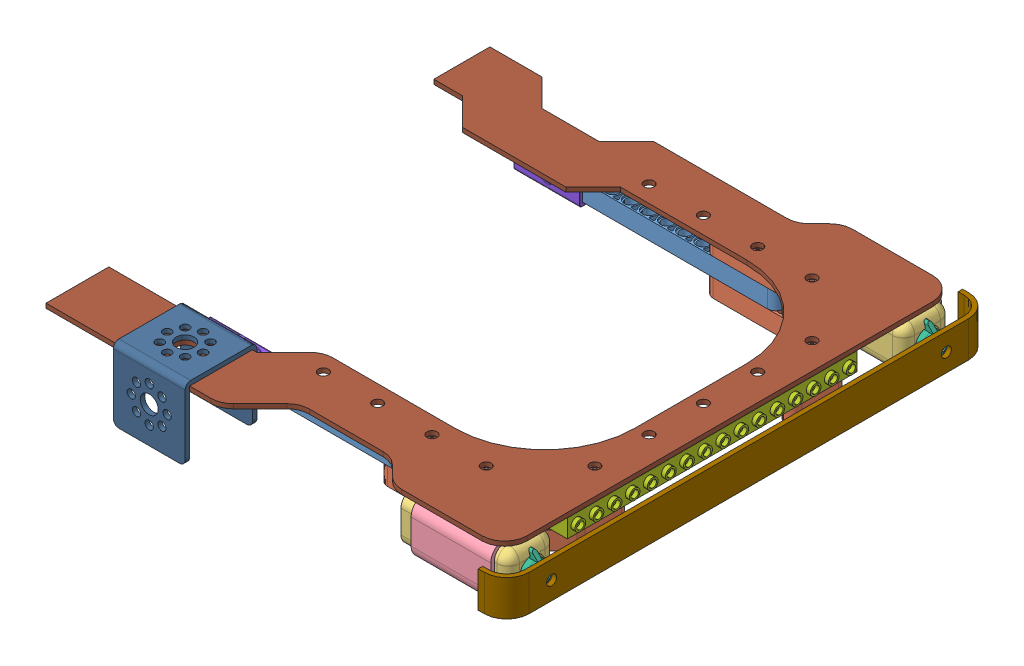
SolidWorks assembly Bump Sensor Assembly, configuration Default. Lengths in mm.
Overall size (205.36 32 217.88).
22 component instances, 11 part files, 41 mates.
Components (placement in the parent):
- Beam 15-1: Beam 15 [Default] at (-13.6618 55.1538 95.9616) size (120.35 8.06 7.44)
- Beam 15-2: Beam 15 [Default] at (-13.6618 55.1538 -49.2084) size (120.35 8.06 7.44)
- Beam Angle 9x5-1: Beam Angle 9x5 [Default] at (75.0532 51.1213 95.9616) x (-1 0 0) z (0 0 1) size (71.96 8.06 39.7)
- Beam Angle 9x5-2: Beam Angle 9x5 [Default] at (75.0532 67.2513 95.9616) x (-1 0 0) z (0 0 1) size (71.96 8.06 39.7)
- Beam Angle 9x5-3: Beam Angle 9x5 [Default] at (75.0532 51.1213 -49.2084) x (-1 0 0) z (0 0 -1) size (71.96 8.06 39.7)
- Beam Angle 9x5-4: Beam Angle 9x5 [Default] at (75.0532 67.2513 -49.2084) x (-1 0 0) z (0 0 -1) size (71.96 8.06 39.7)
- Sensor Touch-1: Sensor Touch [Default] at (127.4932 59.0788 111.4716) x (0 1 0) z (1 0 0) size (24.05 31.58 54.37)
  - Sensor Touch Body-1: Sensor Touch Body [Default] x (-1 0 0) z (0 -1 0) size (22.43 50.04 29.96)
  - Sensor Touch Cover-1: Sensor Touch Cover [Default] at (0 -0.0225 17.75) x (-1 0 0) z (0 0 -1) size (23.6 12.37 35.5)
  - NXT Socket-1: NXT Socket [Default] at (0 -1.35 -23.9) x (-1 0 0) z (0 0 1) size (12.5 15 12.59)
  - Sensor Touch Button-1: Sensor Touch Button [Default] at (0 0 20.4) x (-1 0 0) z (0 1 0) size (16.15 9.9 16.15)
- Sensor Touch-2: Sensor Touch [Default] at (127.4932 59.0788 -64.7184) x (0 -1 0) z (1 0 0) size (24.05 31.58 54.37)
  - Sensor Touch Body-1: Sensor Touch Body [Default] x (-1 0 0) z (0 -1 0) size (22.43 50.04 29.96)
  - Sensor Touch Cover-1: Sensor Touch Cover [Default] at (0 -0.0225 17.75) x (-1 0 0) z (0 0 -1) size (23.6 12.37 35.5)
  - NXT Socket-1: NXT Socket [Default] at (0 -1.35 -23.9) x (-1 0 0) z (0 0 1) size (12.5 15 12.59)
  - Sensor Touch Button-1: Sensor Touch Button [Default] at (0 0 20.4) x (-1 0 0) z (0 1 0) size (16.15 9.9 16.15)
- Stud Beam 16-1: Stud Beam 16 [Default] at (138.6172 59.1863 23.3766) x (0 0 1) z (-1 0 0) size (129.04 8.06 11.46)
- Tetrix Lego Mount-1: Tetrix Lego Mount [Default] at (2.4032 59.2188 101.2116) x (0 -1 0) z (1 0 0) size (24.2 11.25 29.5)
- Tetrix Lego Mount-2: Tetrix Lego Mount [Default] at (2.4032 59.2188 -54.4584) x (0 -1 0) z (-1 0 0) size (24.2 11.25 29.5)
- Bumper-1: Bumper [Default] at (157.7652 51.0788 129.2316) x (0 0 -1) z (1 0 0) size (215.9 16 12.7)
- Tetrix Channel 32mm-1: Tetrix Channel 32mm [Default] at (2.4032 75.2188 117.2116) x (0 0 1) z (1 0 0) size (32 32 32)
- Top Plate-1: Top Plate [Default] at (35.2382 71.2838 88.3766) x (0 0 -1) z (1 0 0) size (208.28 2 196.99)
Mates (geometry in assembly coordinates):
- Coincident1: coincident anti-aligned: plane of Beam 15-1 through (-13.6618 63.2188 95.9616) normal (0 1 0); plane of Beam Angle 9x5-2 through (75.0532 63.2188 95.9616) normal (0 -1 0)
- Coincident2: coincident anti-aligned: plane of Beam 15-1 through (-13.6618 55.1538 95.9616) normal (0 -1 0); plane of Beam Angle 9x5-1 through (75.0532 55.1538 95.9616) normal (0 1 0)
- Concentric1: concentric aligned: cylinder of Beam Angle 9x5-1 through (83.1182 55.1538 95.9616) axis (0 -1 0) radius 2.39; cylinder of Beam Angle 9x5-2 through (83.1182 71.2838 95.9616) axis (0 -1 0) radius 2.39
- Concentric2: concentric aligned: cylinder of Beam Angle 9x5-1 through (139.5732 55.1538 71.7666) axis (0 -1 0) radius 2.39; cylinder of Beam Angle 9x5-2 through (139.5732 71.2838 71.7666) axis (0 -1 0) radius 2.39
- Concentric3: concentric anti-aligned: cylinder of Beam 15-1 through (99.2482 63.2188 95.9616) axis (0 1 0) radius 2.39; cylinder of Beam Angle 9x5-2 through (99.2482 71.2838 95.9616) axis (0 -1 0) radius 2.39
- Concentric5: concentric anti-aligned: cylinder of Beam 15-1 through (83.1182 63.2188 95.9616) axis (0 1 0) radius 2.39; cylinder of Beam Angle 9x5-2 through (83.1182 71.2838 95.9616) axis (0 -1 0) radius 2.39
- Coincident3: coincident anti-aligned: plane of Beam Angle 9x5-1 through (75.0532 55.1538 95.9616) normal (0 1 0); plane of Sensor Touch-1/Sensor Touch Body-1 through (127.1632 55.1538 100.7416) normal (0 -1 0)
- Concentric6: concentric aligned: cylinder of Beam Angle 9x5-1 through (123.4432 55.1538 95.9616) axis (0 -1 0) radius 2.39; cylinder of Sensor Touch-1/Sensor Touch Body-1 through (123.4432 55.1538 95.9616) axis (0 -1 0) radius 2.39
- Concentric7: concentric aligned: cylinder of Beam Angle 9x5-2 through (107.3132 71.2838 95.9616) axis (0 -1 0) radius 2.39; cylinder of Sensor Touch-1/Sensor Touch Body-1 through (107.3132 55.1538 95.9616) axis (0 -1 0) radius 2.39
- Concentric11: concentric aligned: cylinder of Beam Angle 9x5-3 through (139.5732 47.0888 -25.0134) axis (0 1 0) radius 2.39; cylinder of Beam Angle 9x5-4 through (139.5732 63.2188 -25.0134) axis (0 1 0) radius 2.39
- Coincident9: coincident anti-aligned: plane of Beam Angle 9x5-3 through (75.0532 55.1538 -49.2084) normal (0 1 0); plane of Sensor Touch-2/Sensor Touch Body-1 through (103.5932 55.1538 -53.9884) normal (0 -1 0)
- Concentric12: concentric aligned: cylinder of Beam Angle 9x5-3 through (123.4432 47.0888 -49.2084) axis (0 1 0) radius 2.39; cylinder of Sensor Touch-2/Sensor Touch Body-1 through (123.4432 63.0038 -49.2084) axis (0 1 0) radius 2.39
- Concentric13: concentric aligned: cylinder of Beam Angle 9x5-4 through (107.3132 63.2188 -49.2084) axis (0 1 0) radius 2.39; cylinder of Sensor Touch-2/Sensor Touch Body-1 through (107.3132 63.0038 -49.2084) axis (0 1 0) radius 2.39
- Concentric14: concentric aligned: cylinder of Beam 15-2 through (99.2482 63.2188 -49.2084) axis (0 1 0) radius 2.39; cylinder of Beam Angle 9x5-3 through (99.2482 47.0888 -49.2084) axis (0 1 0) radius 2.39
- Concentric15: concentric aligned: cylinder of Beam 15-2 through (83.1182 63.2188 -49.2084) axis (0 1 0) radius 2.39; cylinder of Beam Angle 9x5-3 through (83.1182 47.0888 -49.2084) axis (0 1 0) radius 2.39
- Coincident10: coincident aligned: plane of Beam 15-2 through (99.2482 55.1538 -52.9284) normal (0 0 -1); plane of Beam Angle 9x5-4 through (124.9841 63.2188 -52.9284) normal (0 0 -1)
- Coincident11: coincident anti-aligned: plane of Beam 15-2 through (-13.6618 55.1538 -49.2084) normal (0 -1 0); plane of Beam Angle 9x5-3 through (75.0532 55.1538 -49.2084) normal (0 1 0)
- Concentric16: concentric anti-aligned: cylinder of Beam Angle 9x5-2 through (139.5732 71.2838 79.8316) axis (0 -1 0) radius 2.39; cylinder of Stud Beam 16-1 through (139.5732 63.2188 79.8316) axis (0 1 0) radius 2.39
- Concentric17: concentric anti-aligned: cylinder of Beam Angle 9x5-2 through (139.5732 71.2838 71.7666) axis (0 -1 0) radius 2.39; cylinder of Stud Beam 16-1 through (139.5732 63.2188 71.7666) axis (0 1 0) radius 2.39
- Coincident12: coincident anti-aligned: plane of Beam Angle 9x5-1 through (75.0532 55.1538 95.9616) normal (0 1 0); plane of Stud Beam 16-1 through (138.6172 55.1538 23.3766) normal (0 -1 0)
- Coincident13: coincident aligned: plane of Beam 15-2 through (99.2482 55.1538 -52.9284) normal (0 0 -1); plane of Beam Angle 9x5-4 through (124.9841 63.2188 -52.9284) normal (0 0 -1)
- Coincident14: coincident anti-aligned: plane of Beam Angle 9x5-3 through (75.0532 55.1538 -49.2084) normal (0 1 0); plane of Stud Beam 16-1 through (138.6172 55.1538 23.3766) normal (0 -1 0)
- Coincident15: coincident anti-aligned: plane of Beam Angle 9x5-4 through (75.0532 63.2188 -49.2084) normal (0 -1 0); plane of Stud Beam 16-1 through (138.6172 63.2188 23.3766) normal (0 1 0)
- Concentric18: concentric aligned: cylinder of Beam Angle 9x5-4 through (139.5732 63.2188 -25.0134) axis (0 1 0) radius 2.39; cylinder of Stud Beam 16-1 through (139.5732 63.2188 -25.0134) axis (0 1 0) radius 2.39
- Concentric19: concentric aligned: cylinder of Beam Angle 9x5-4 through (139.5732 63.2188 -33.0784) axis (0 1 0) radius 2.39; cylinder of Stud Beam 16-1 through (139.5732 63.2188 -33.0784) axis (0 1 0) radius 2.39
- Coincident16: coincident anti-aligned: plane of Beam 15-1 through (-13.6618 63.2188 95.9616) normal (0 1 0); plane of Tetrix Lego Mount-1 through (-12.3468 63.2188 99.8116) normal (0 -1 0)
- Concentric20: concentric anti-aligned: cylinder of Beam 15-1 through (-5.5968 63.2188 95.9616) axis (0 1 0) radius 2.39; cylinder of Tetrix Lego Mount-1 through (-5.5968 73.7388 95.9616) axis (0 -1 0) radius 3.1
- Parallel3: parallel aligned: plane of Beam 15-1 through (99.2482 55.1538 92.2416) normal (0 0 -1); plane of Tetrix Lego Mount-1 through (-12.3468 53.7188 90.7116) normal (0 0 -1)
- Coincident18: coincident anti-aligned: plane of Beam 15-2 through (-13.6618 63.2188 -49.2084) normal (0 1 0); plane of Tetrix Lego Mount-2 through (17.1532 63.2188 -53.0584) normal (0 -1 0)
- Concentric22: concentric anti-aligned: cylinder of Beam 15-2 through (-5.5968 63.2188 -49.2084) axis (0 1 0) radius 2.39; cylinder of Tetrix Lego Mount-2 through (-5.5968 73.7388 -49.2084) axis (0 -1 0) radius 3.1
- Parallel4: parallel anti-aligned: plane of Beam 15-2 through (99.2482 55.1538 -52.9284) normal (0 0 -1); plane of Tetrix Lego Mount-2 through (17.1532 55.2188 -53.0584) normal (0 0 1)
- Parallel5: parallel anti-aligned: plane of Stud Beam 16-1 through (143.4562 55.1538 87.8966) normal (1 0 0); plane of Bumper-1 through (157.7652 67.0788 129.2316) normal (-1 0 0)
- Concentric23: concentric aligned: cylinder of Sensor Touch-2/Sensor Touch Body-1 through (151.3932 59.0788 -64.7184) axis (1 0 0) radius 5.6; cylinder of Bumper-1 through (147.0652 59.0788 -64.7184) axis (1 0 0) radius 2.25
- Parallel6: parallel aligned: plane of Stud Beam 16-1 through (138.6172 63.2188 23.3766) normal (0 1 0); plane of Bumper-1 through (157.7652 67.0788 129.2316) normal (0 1 0)
- Coincident22: coincident: moEndPointRef_w of Sensor Touch-2/Sensor Touch Button-1; plane of Bumper-1 through (157.7652 67.0788 129.2316) normal (-1 0 0)
- Coincident23: coincident anti-aligned: plane of Tetrix Lego Mount-1 through (2.4032 59.2188 101.2116) normal (0 0 1); plane of Tetrix Channel 32mm-1 through (-13.5968 43.2188 101.2116) normal (0 0 -1)
- Concentric24: concentric anti-aligned: cylinder of Tetrix Lego Mount-1 through (2.4032 51.2188 101.2116) axis (0 0 -1) radius 1.75; cylinder of Tetrix Channel 32mm-1 through (2.4032 51.2188 133.2116) axis (0 0 1) radius 1.85
- Concentric25: concentric anti-aligned: cylinder of Tetrix Lego Mount-1 through (2.4032 67.2188 101.2116) axis (0 0 -1) radius 1.75; cylinder of Tetrix Channel 32mm-1 through (2.4032 67.2188 133.2116) axis (0 0 1) radius 1.85
- Coincident24: coincident anti-aligned: plane of Beam Angle 9x5-4 through (75.0532 71.2838 -49.2084) normal (0 1 0); plane of Top Plate-1 through (35.2382 71.2838 88.3766) normal (0 -1 0)
- Coincident25: coincident aligned: plane of Sensor Touch-2/Sensor Touch Body-1 through (151.3932 59.0788 -64.7184) normal (1 0 0); plane of Top Plate-1 through (151.3932 73.2838 -77.0684) normal (1 0 0)
- Coincident26: coincident: plane of Tetrix Channel 32mm-1 through (-13.5968 43.2188 131.2116) normal (0 0 -1); line of Top Plate-1 through (-35.5968 71.2838 131.2116) axis (1 0 0)
